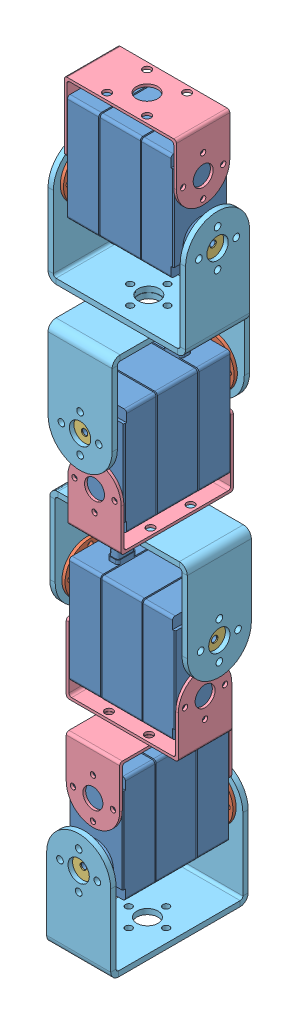
SolidWorks assembly Leg 1, configuration Default. Lengths in mm.
Overall size (51.53 269.48 51.53).
24 component instances, 5 part files, 12 mates.
Components (placement in the parent):
- Assembly-1: Assembly [Default] at (24.006 72.7387 32.0964) x (0 -1 0) z (0 0 1) size (67.3 51.5 26.87)
  - dual shaft servo-1: dual shaft servo [Predeterminado] at (14.992 2.8195 38.2318) size (46.51 48.8 20.07)
  - accessory 1-1: accessory 1 [Predeterminado] at (35.7217 1.0691 58.2951) x (0.70399 0 0.71021) z (0.71021 0 -0.70399) size (19 2.2 19)
  - accessory 2-2: accessory 2 [Predeterminado] at (7.8921 46.4181 29.4135) x (-0.683613 0 -0.729844) z (0.729844 0 -0.683613) size (19 3.2 19)
  - support 1 ( dimensions check)-1: support 1 ( dimensions check) [Predeterminado] at (-9.1537 29.6478 38.798) x (0 1 0) z (0 0 -1) size (42 26 20)
  - U Bracket-1: U Bracket [Défaut] at (58.1419 23.5615 38.2647) x (0 -1 0) z (0 0 -1) size (51.5 42 24)
- Assembly-2: Assembly [Default] at (9.3028 -43.6451 46.7996) x (0 1 0) z (1 0 0) size (67.3 51.5 26.87)
  - dual shaft servo-1: dual shaft servo [Predeterminado] at (14.992 2.8195 38.2318) size (46.51 48.8 20.07)
  - accessory 1-1: accessory 1 [Predeterminado] at (35.7217 1.0691 58.2951) x (0.70399 0 0.71021) z (0.71021 0 -0.70399) size (19 2.2 19)
  - accessory 2-2: accessory 2 [Predeterminado] at (7.8921 46.4181 29.4135) x (-0.683613 0 -0.729844) z (0.729844 0 -0.683613) size (19 3.2 19)
  - support 1 ( dimensions check)-1: support 1 ( dimensions check) [Predeterminado] at (-9.1537 29.6478 38.798) x (0 1 0) z (0 0 -1) size (42 26 20)
  - U Bracket-1: U Bracket [Défaut] at (58.1419 23.5615 38.2647) x (0 -1 0) z (0 0 -1) size (51.5 42 24)
- Assembly-3: Assembly [Default] at (24.0393 -111.0408 107.9997) x (0 1 0) z (0 0 -1) size (67.3 51.5 26.87)
  - dual shaft servo-1: dual shaft servo [Predeterminado] at (14.992 2.8195 38.2318) size (46.51 48.8 20.07)
  - accessory 1-1: accessory 1 [Predeterminado] at (35.7217 1.0691 58.2951) x (0.70399 0 0.71021) z (0.71021 0 -0.70399) size (19 2.2 19)
  - accessory 2-2: accessory 2 [Predeterminado] at (7.8921 46.4181 29.4135) x (-0.683613 0 -0.729844) z (0.729844 0 -0.683613) size (19 3.2 19)
  - support 1 ( dimensions check)-1: support 1 ( dimensions check) [Predeterminado] at (-9.1537 29.6478 38.798) x (0 1 0) z (0 0 -1) size (42 26 20)
  - U Bracket-1: U Bracket [Défaut] at (58.1419 23.5615 38.2647) x (0 -1 0) z (0 0 -1) size (51.5 42 24)
- Assembly-4: Assembly [Default] at (85.2726 -129.4482 46.7664) x (0 -1 0) z (-1 0 0) size (67.3 51.5 26.87)
  - dual shaft servo-1: dual shaft servo [Predeterminado] at (14.992 2.8195 38.2318) size (46.51 48.8 20.07)
  - accessory 1-1: accessory 1 [Predeterminado] at (35.7217 1.0691 58.2951) x (0.70399 0 0.71021) z (0.71021 0 -0.70399) size (19 2.2 19)
  - accessory 2-2: accessory 2 [Predeterminado] at (7.8921 46.4181 29.4135) x (-0.683613 0 -0.729844) z (0.729844 0 -0.683613) size (19 3.2 19)
  - support 1 ( dimensions check)-1: support 1 ( dimensions check) [Predeterminado] at (-9.1537 29.6478 38.798) x (0 1 0) z (0 0 -1) size (42 26 20)
  - U Bracket-1: U Bracket [Défaut] at (58.1419 23.5615 38.2647) x (0 -1 0) z (0 0 -1) size (51.5 42 24)
Mates (geometry in assembly coordinates):
- Parallel4: parallel anti-aligned: plane of Assembly-1/U Bracket-1 through (73.3175 14.5968 58.3611) normal (0 -1 0); plane of Assembly-2/U Bracket-1 through (35.5675 14.4968 96.1111) normal (0 1 0)
- Concentric8: concentric anti-aligned: circle of Assembly-1/U Bracket-1; circle of Assembly-2/U Bracket-1
- Distance6: distance = 0.1 mm anti-aligned: plane of Assembly-1/U Bracket-1 through (73.3175 14.5968 58.3611) normal (0 -1 0); plane of Assembly-2/U Bracket-1 through (35.5675 14.4968 96.1111) normal (0 1 0)
- Parallel5: parallel anti-aligned: plane of Assembly-2/support 1 ( dimensions check)-1 through (48.1008 -52.7988 76.4474) normal (0 -1 0); plane of Assembly-3/U Bracket-1 through (73.3508 -52.8988 81.735) normal (0 1 0)
- Concentric9: concentric aligned: circle of Assembly-2/support 1 ( dimensions check)-1; circle of Assembly-3/U Bracket-1
- Distance8: distance = 0.1 mm anti-aligned: plane of Assembly-2/support 1 ( dimensions check)-1 through (48.1008 -52.7988 76.4474) normal (0 -1 0); plane of Assembly-3/U Bracket-1 through (73.3508 -52.8988 81.735) normal (0 1 0)
- Perpendicular13: perpendicular: plane of Assembly-1/U Bracket-1 through (71.3175 17.5968 82.3611) normal (0 0 1); line of Assembly-2/U Bracket-1 through (47.5675 14.4968 96.1111) axis (0 0 -1)
- Perpendicular14: perpendicular: plane of Assembly-2/support 1 ( dimensions check)-1 through (37.6008 -51.7988 48.735) normal (-1 0 0); plane of Assembly-3/U Bracket-1 through (23.8508 -55.8988 81.735) normal (0 0 1)
- Parallel6: parallel anti-aligned: plane of Assembly-3/support 1 ( dimensions check)-1 through (53.6871 -120.1945 69.2017) normal (0 -1 0); plane of Assembly-4/support 1 ( dimensions check)-1 through (46.4746 -120.2945 76.4142) normal (0 1 0)
- Concentric10: concentric anti-aligned: circle of Assembly-3/support 1 ( dimensions check)-1; circle of Assembly-4/support 1 ( dimensions check)-1
- Perpendicular15: perpendicular: plane of Assembly-3/support 1 ( dimensions check)-1 through (25.9746 -119.1945 79.7017) normal (0 0 1); line of Assembly-4/support 1 ( dimensions check)-1 through (36.9746 -121.2945 88.7017) axis (0 0 -1)
- Distance10: distance = 0.1 mm anti-aligned: plane of Assembly-3/support 1 ( dimensions check)-1 through (53.6871 -120.1945 69.2017) normal (0 -1 0); plane of Assembly-4/support 1 ( dimensions check)-1 through (46.4746 -120.2945 76.4142) normal (0 1 0)
